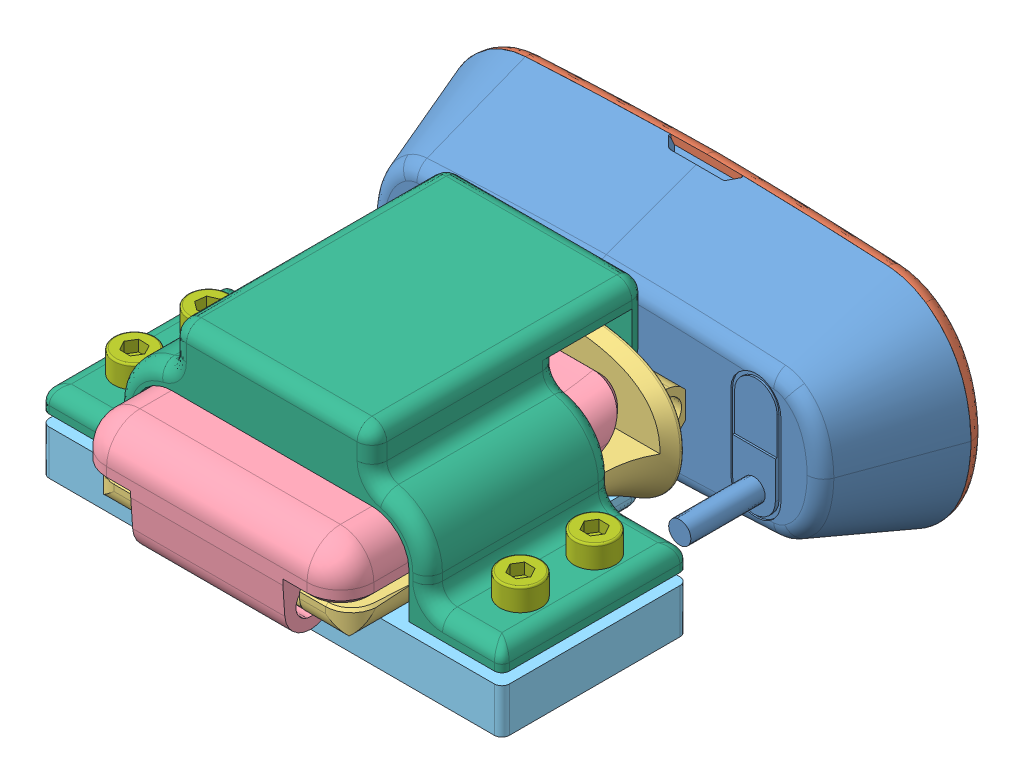
SolidWorks assembly cam-c310-monte, configuration Défaut. Lengths in mm.
Overall size (71.5 31.83 69.48).
15 component instances, 8 part files, 32 mates.
Components (placement in the parent):
- c310-1: c310 [Défaut] at (4.1302 -12.061 -110.284) x (-1 0 0) z (0 0 1) size (71.5 31.65 69.48)
  - c310-corps-1: c310-corps [Default] at (1.7129 6.6622 61.3001) size (71.27 31.35 30.56)
  - c310-cache-1: c310-cache [Default] at (1.7129 6.6622 59.0501) x (-1 0 0) z (0 0 -1) size (71.5 31.65 2.5)
  - clip-1-1: clip-1 [Default] at (4.1303 6.6622 81.7235) x (-1 0 0) z (0 0 1) size (43.19 23.62 48.27)
  - clip-2-1: clip-2 [Default] at (4.8803 2.4122 105.5985) x (-1 0 0) z (0 0 -1) size (36 14.88 39.47)
- cam-mount-1-1: cam-mount-1 [Défaut] at (-0.7501 -29.7231 -6.0605) size (62 8 37)
- cam-mount-2-1: cam-mount-2 [Défaut] at (-0.7501 -22.2204 -18.5605) size (62 19.5 37)
- vis-chc-1: vis-chc [Vis CHC M3x10] at (25.2468 -19.2204 -1.0605) x (1 0 0) z (0 0 1) size (5.5 13 5.5)
- vis-chc-2: vis-chc [Vis CHC M3x10] at (25.2468 -19.2204 -11.0605) x (1 0 0) z (0 0 1) size (5.5 13 5.5)
- ecrou-h-1: ecrou-h [6012 HU M3] at (25.2468 -26.7231 -11.0605) x (0.5 0 -0.866025) z (0.866025 0 0.5) size (5.5 2.4 6.35)
- vis-chc-3: vis-chc [Vis CHC M3x10] at (-26.7501 -19.2204 -1.0605) x (0.999999 0 -0.001191) z (0.001191 0 0.999999) size (5.5 13 5.5)
- vis-chc-4: vis-chc [Vis CHC M3x10] at (-26.7501 -19.2204 -11.0605) x (0.814665 0 0.579932) z (-0.579932 0 0.814665) size (5.5 13 5.5)
- ecrou-h-2: ecrou-h [6012 HU M3] at (25.2468 -26.7231 -1.0605) x (0.5 0 -0.866025) z (0.866025 0 0.5) size (5.5 2.4 6.35)
- ecrou-h-3: ecrou-h [6012 HU M3] at (-26.7501 -26.7231 -1.0605) x (0.5 0 -0.866025) z (0.866025 0 0.5) size (5.5 2.4 6.35)
- ecrou-h-4: ecrou-h [6012 HU M3] at (-26.7501 -26.7231 -11.0605) x (0.5 0 0.866025) z (-0.866025 0 0.5) size (5.5 2.4 6.35)
Mates (geometry in assembly coordinates):
- Parallèle7: parallel anti-aligned: plane of cam-mount-1-1 through (-1.2501 -23.7231 -6.0605) normal (0 1 0); plane of cam-mount-2-1 through (-19.7501 -22.2204 6.4395) normal (0 -1 0)
- Parallèle8: parallel aligned: plane of cam-mount-1-1 through (-32.2501 -23.7231 6.4395) normal (0 0 1); plane of cam-mount-2-1 through (12.2499 -16.2231 6.4395) normal (0 0 1)
- Coïncidente12: coincident aligned: plane of cam-mount-1-1 through (-32.2501 -23.7231 6.4395) normal (-1 0 0); plane of cam-mount-2-1 through (-32.2501 -22.2204 -18.5605) normal (-1 0 0)
- Coïncidente13: coincident aligned: plane of cam-mount-1-1 through (-32.2501 -23.7231 -18.5605) normal (0 0 -1); plane of cam-mount-2-1 through (12.2499 -16.2231 -18.5605) normal (0 0 -1)
- Coaxiale1: concentric aligned: cylinder of cam-mount-2-1 through (24.7468 -22.2214 -1.0605) axis (0 1 0) radius 1.6; cylinder of vis-chc-1 through (24.7468 -29.2204 -1.0605) axis (0 1 0) radius 1.5
- Coaxiale3: concentric aligned: cylinder of cam-mount-2-1 through (24.7468 -22.2214 -11.0605) axis (0 1 0) radius 1.6; cylinder of vis-chc-2 through (24.7468 -29.2204 -11.0605) axis (0 1 0) radius 1.5
- Coïncidente14: coincident anti-aligned: plane of cam-mount-2-1 through (29.7499 -19.2204 6.4395) normal (0 1 0); plane of vis-chc-2 through (24.7468 -19.2204 -11.0605) normal (0 -1 0)
- Coïncidente15: coincident anti-aligned: plane of cam-mount-2-1 through (29.7499 -19.2204 6.4395) normal (0 1 0); plane of vis-chc-1 through (24.7468 -19.2204 -1.0605) normal (0 -1 0)
- Coaxiale4: concentric aligned: cylinder of vis-chc-2 through (24.7468 -29.2204 -11.0605) axis (0 1 0) radius 1.5; cylinder of ecrou-h-1 through (24.7468 -29.1231 -11.0605) axis (0 1 0) radius 1.2295
- Coïncidente22: coincident anti-aligned: plane of cam-mount-1-1 through (-1.2501 -26.7231 -6.0605) normal (0 -1 0); plane of ecrou-h-1 through (24.7468 -26.7231 -14.2359) normal (0 1 0)
- Parallèle11: parallel anti-aligned: plane of cam-mount-1-1 through (24.7499 -26.7231 -14.5605) normal (-0.5 0 0.866025); plane of ecrou-h-1 through (27.4968 -29.1231 -12.6482) normal (0.5 0 -0.866025)
- Coaxiale5: concentric aligned: cylinder of cam-mount-2-1 through (-27.2501 -22.2214 -11.0605) axis (0 1 0) radius 1.6; cylinder of vis-chc-4 through (-27.2501 -29.2204 -11.0605) axis (0 1 0) radius 1.5
- Coaxiale6: concentric aligned: cylinder of cam-mount-2-1 through (-27.2501 -22.2214 -1.0605) axis (0 1 0) radius 1.6; cylinder of vis-chc-3 through (-27.2501 -29.2204 -1.0605) axis (0 1 0) radius 1.5
- Coïncidente24: coincident anti-aligned: plane of cam-mount-2-1 through (-32.2501 -19.2204 -18.5605) normal (0 1 0); plane of vis-chc-3 through (-27.2501 -19.2204 -1.0605) normal (0 -1 0)
- Coïncidente25: coincident anti-aligned: plane of cam-mount-2-1 through (-32.2501 -19.2204 -18.5605) normal (0 1 0); plane of vis-chc-4 through (-27.2501 -19.2204 -11.0605) normal (0 -1 0)
- Coaxiale7: concentric aligned: cylinder of vis-chc-4 through (-27.2501 -29.2204 -11.0605) axis (0 1 0) radius 1.5; cylinder of ecrou-h-4 through (-27.2501 -29.1231 -11.0605) axis (0 1 0) radius 1.2295
- Coaxiale8: concentric aligned: cylinder of vis-chc-3 through (-27.2501 -29.2204 -1.0605) axis (0 1 0) radius 1.5; cylinder of ecrou-h-3 through (-27.2501 -29.1231 -1.0605) axis (0 1 0) radius 1.2295
- Coaxiale10: concentric aligned: cylinder of vis-chc-1 through (24.7468 -29.2204 -1.0605) axis (0 1 0) radius 1.5; cylinder of ecrou-h-2 through (24.7468 -29.1231 -1.0605) axis (0 1 0) radius 1.2295
- Coïncidente26: coincident anti-aligned: plane of cam-mount-1-1 through (-1.2501 -26.7231 -6.0605) normal (0 -1 0); plane of ecrou-h-2 through (24.7468 -26.7231 -4.2359) normal (0 1 0)
- Parallèle12: parallel anti-aligned: plane of cam-mount-1-1 through (27.781 -26.7231 -2.8105) normal (-1 0 0); plane of ecrou-h-2 through (27.4968 -29.1231 0.5272) normal (1 0 0)
- Parallèle13: parallel anti-aligned: plane of cam-mount-1-1 through (-30.2812 -26.7231 0.6895) normal (1 0 0); plane of ecrou-h-3 through (-30.0001 -29.1231 -2.6482) normal (-1 0 0)
- Coïncidente30: coincident anti-aligned: plane of cam-mount-1-1 through (-1.2501 -26.7231 -6.0605) normal (0 -1 0); plane of ecrou-h-3 through (-27.2501 -26.7231 -4.2359) normal (0 1 0)
- Coïncidente31: coincident anti-aligned: plane of cam-mount-1-1 through (-1.2501 -26.7231 -6.0605) normal (0 -1 0); plane of ecrou-h-4 through (-24.5001 -26.7231 -9.4728) normal (0 1 0)
- Parallèle14: parallel anti-aligned: plane of cam-mount-1-1 through (-27.2501 -26.7231 -7.5605) normal (0.5 0 -0.866025); plane of ecrou-h-4 through (-30.0001 -29.1231 -9.4728) normal (-0.5 0 0.866025)
- Parallèle15: parallel: plane of assembly through (0 0 0) normal (0 1 0); plane of cam-mount-2-1 through (-19.88 -2.7231 -18.5605) normal (0 1 0); plane of assembly
- Coïncidente38: coincident anti-aligned: plane of c310-1/clip-1-1 through (-17.2567 -27.8206 -28.5605) normal (0 0 -1); plane of cam-mount-2-1 through (-14.7501 -11.7231 -28.5605) normal (0 0 1)
- Coïncidente39: coincident: line of c310-1/clip-2-1 through (12.7499 -11.2231 -14.5605) axis (-1 0 0); plane of cam-mount-2-1 through (-14.7501 -11.2231 6.4395) normal (0 -1 0)
- Coïncidente41: coincident: line of c310-1/clip-1-1 through (-0.7501 -23.7231 6.4395) axis (0 0 -1); plane of cam-mount-1-1 through (-1.2501 -23.7231 -6.0605) normal (0 1 0)
- Coïncidente43: coincident: point of c310-1/clip-1-1
- Parallèle21: parallel aligned: plane of c310-1/clip-1-1 through (35.9999 -18.7231 -26.5605) normal (0 0 1)
- Parallèle22: parallel aligned: plane of c310-1/clip-1-1 through (14.5423 -22.2231 -34.5605) normal (1 0 0)
- Distance1: distance = 0.5 mm anti-aligned: plane of c310-1/clip-2-1 through (-18.7501 -14.4731 -4.6855) normal (-1 0 0); plane of cam-mount-2-1 through (-19.2501 -22.2204 6.4395) normal (1 0 0)
